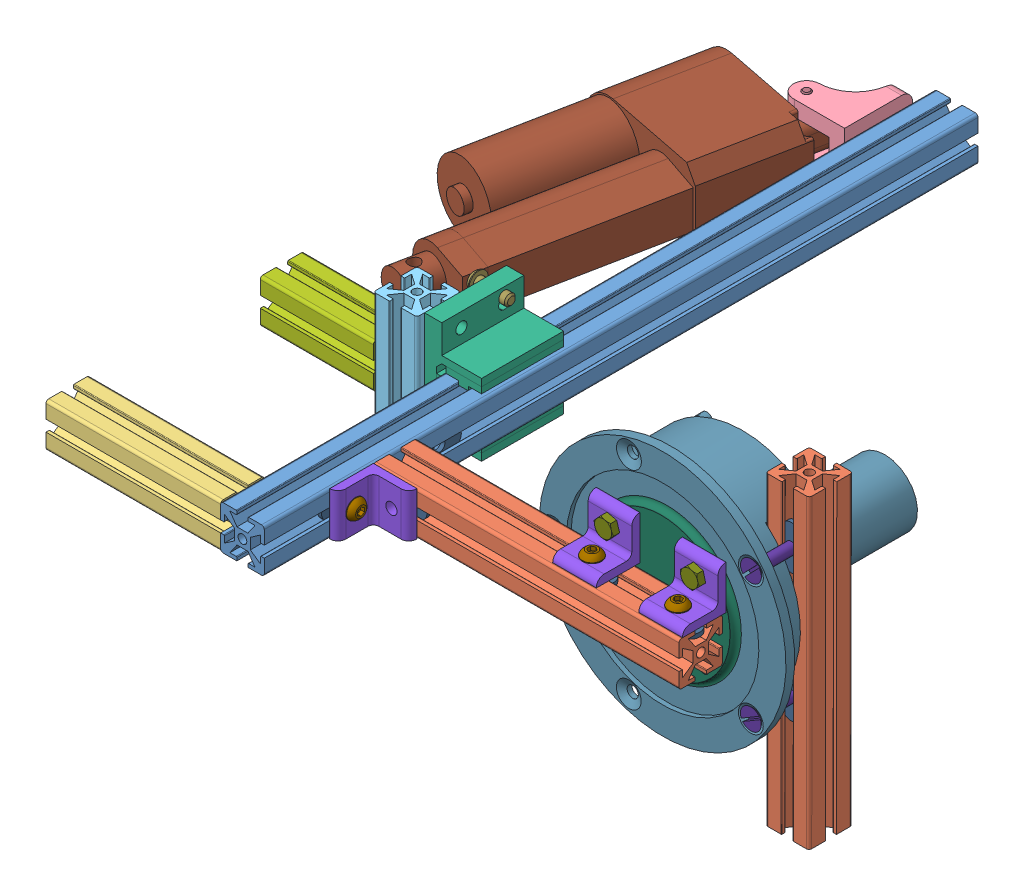
SolidWorks assembly ball manipulator stand, configuration Default. Lengths in mm.
Overall size (319.83 198.44 212.31).
77 component instances, 17 part files, 145 mates.
Components (placement in the parent):
- 80-20 Extrusion- 16.5in-1: 80-20 Extrusion- 16.5in [80-20 Extrusion - 12.0 inch] at (161.9188 214.7859 108.7981) size (25.4 25.4 415.29) (hidden)
- 80-20 Extrusion-7in-1: 80-20 Extrusion-7in [80-20 Extrusion - 12.0 inch] at (352.4188 214.7859 447.8881) x (0 0 1) z (-1 0 0) size (25.4 25.4 177.8)
- 80-20 Extrusion-4in-1: 80-20 Extrusion-4in [80-20 Extrusion - 12.0 inch] at (47.6188 214.7859 511.3881) x (0 0 -1) z (1 0 0) size (25.4 25.4 101.6) (hidden)
- Linear Actuator Mount (10-24)-1: Linear Actuator Mount (10-24) [Default] at (149.2188 233.8359 141.2593) x (0 0 -1) z (0 1 0) size (39.54 37.32 38.1) (hidden)
- 80-20 Extrusion (simplified)-1: 80-20 Extrusion (simplified) [80-20 Extrusion - 12.0 inch] at (126.0142 252.6319 386.5998) x (1 0 0) z (0 -1 0) size (25.4 25.4 101.6) (hidden)
- 80-20 Linear Slide-1: 80-20 Linear Slide [Default] at (171.9374 230.4306 347.2298) x (0 -1 0) z (0 0 1) size (74.8 33.22 47.75) (hidden)
- 80-20 Extrusion-2.59in-1: 80-20 Extrusion-2.59in [80-20 Extrusion - 12.0 inch] at (113.3142 214.7859 386.5998) x (0 0 1) z (-1 0 0) size (25.4 25.4 65.79) (hidden)
- 80-20 90 Degree Bracket Assy-1: 80-20 90 Degree Bracket Assy [Default] at (172.1403 218.357 451.9796) x (0 -1 0) z (0 0 1) size (25.4 35.88 33.34)
  - 80-20 90 Degree Angle Bracket-1: 80-20 90 Degree Angle Bracket [Default] at (-9.1289 2.4785 8.6086) size (25.4 25.4 25.4) (hidden)
  - 0.25-20 Button Head Cap Screw (BHCS)-1: 0.25-20 Button Head Cap Screw (BHCS) [Default] at (3.5711 10.5938 23.8486) x (1 0 0) z (0 -1 0) size (11.1 11.1 16.05) (hidden)
  - 0.25-20 Button Head Cap Screw (BHCS)-2: 0.25-20 Button Head Cap Screw (BHCS) [Default] at (3.5711 17.7185 16.7239) x (1 0 0) z (0 0 -1) size (11.1 11.1 16.05) (hidden)
  - 80-20 0.25-20 T-NUT-2: 80-20 0.25-20 T-NUT [Default] at (-122.3619 -100.634 5.3515) x (0 1 0) z (0 0 -1) size (25.4 11.25 2.41) (hidden)
- 80-20 90 Degree Bracket Assy-2: 80-20 90 Degree Bracket Assy [Default] at (166.0102 218.357 437.6667) x (0 -1 0) z (1 0 0) size (25.4 35.88 33.34)
  - 80-20 90 Degree Angle Bracket-1: 80-20 90 Degree Angle Bracket [Default] at (-9.1289 2.4785 8.6086) size (25.4 25.4 25.4) (hidden)
  - 0.25-20 Button Head Cap Screw (BHCS)-1: 0.25-20 Button Head Cap Screw (BHCS) [Default] at (3.5711 10.5938 23.8486) x (1 0 0) z (0 -1 0) size (11.1 11.1 16.05) (hidden)
  - 0.25-20 Button Head Cap Screw (BHCS)-2: 0.25-20 Button Head Cap Screw (BHCS) [Default] at (3.5711 17.7185 16.7239) x (1 0 0) z (0 0 -1) size (11.1 11.1 16.05) (hidden)
  - 80-20 0.25-20 T-NUT-2: 80-20 0.25-20 T-NUT [Default] at (-122.3619 -100.634 5.3515) x (0 1 0) z (0 0 -1) size (25.4 11.25 2.41) (hidden)
- 80-20 90 Degree Bracket Assy-3: 80-20 90 Degree Bracket Assy [Default] at (115.7927 218.8774 390.1709) x (0 0 -1) z (0 1 0) size (25.4 35.88 33.34) (hidden)
  - 80-20 90 Degree Angle Bracket-1: 80-20 90 Degree Angle Bracket [Default] at (-9.1289 2.4785 8.6086) size (25.4 25.4 25.4) (hidden)
  - 0.25-20 Button Head Cap Screw (BHCS)-1: 0.25-20 Button Head Cap Screw (BHCS) [Default] at (3.5711 10.5938 23.8486) x (1 0 0) z (0 -1 0) size (11.1 11.1 16.05) (hidden)
  - 0.25-20 Button Head Cap Screw (BHCS)-2: 0.25-20 Button Head Cap Screw (BHCS) [Default] at (3.5711 17.7185 16.7239) x (1 0 0) z (0 0 -1) size (11.1 11.1 16.05) (hidden)
  - 80-20 0.25-20 T-NUT-2: 80-20 0.25-20 T-NUT [Default] at (-122.3619 -100.634 5.3515) x (0 1 0) z (0 0 -1) size (25.4 11.25 2.41) (hidden)
- 80-20 90 Degree Bracket Assy-4: 80-20 90 Degree Bracket Assy [Default] at (115.7927 210.6945 383.0286) x (0 0 1) z (0 -1 0) size (25.4 35.88 33.34) (hidden)
  - 80-20 90 Degree Angle Bracket-1: 80-20 90 Degree Angle Bracket [Default] at (-9.1289 2.4785 8.6086) size (25.4 25.4 25.4) (hidden)
  - 0.25-20 Button Head Cap Screw (BHCS)-1: 0.25-20 Button Head Cap Screw (BHCS) [Default] at (3.5711 10.5938 23.8486) x (1 0 0) z (0 -1 0) size (11.1 11.1 16.05) (hidden)
  - 0.25-20 Button Head Cap Screw (BHCS)-2: 0.25-20 Button Head Cap Screw (BHCS) [Default] at (3.5711 17.7185 16.7239) x (1 0 0) z (0 0 -1) size (11.1 11.1 16.05) (hidden)
  - 80-20 0.25-20 T-NUT-2: 80-20 0.25-20 T-NUT [Default] at (-122.3619 -100.634 5.3515) x (0 1 0) z (0 0 -1) size (25.4 11.25 2.41) (hidden)
- 80-20 90 Degree Bracket Assy-6: 80-20 90 Degree Bracket Assy [Default] at (157.8273 211.2148 501.1667) x (0 1 0) z (-1 0 0) size (25.4 35.88 33.34)
  - 80-20 90 Degree Angle Bracket-1: 80-20 90 Degree Angle Bracket [Default] at (-9.1289 2.4785 8.6086) size (25.4 25.4 25.4) (hidden)
  - 0.25-20 Button Head Cap Screw (BHCS)-1: 0.25-20 Button Head Cap Screw (BHCS) [Default] at (3.5711 10.5938 23.8486) x (1 0 0) z (0 -1 0) size (11.1 11.1 16.05) (hidden)
  - 0.25-20 Button Head Cap Screw (BHCS)-2: 0.25-20 Button Head Cap Screw (BHCS) [Default] at (3.5711 17.7185 16.7239) x (1 0 0) z (0 0 -1) size (11.1 11.1 16.05) (hidden)
  - 80-20 0.25-20 T-NUT-2: 80-20 0.25-20 T-NUT [Default] at (-122.3619 -100.634 5.3515) x (0 1 0) z (0 0 -1) size (25.4 11.25 2.41) (hidden)
- Linear Actuator Mount (10-24)-2: Linear Actuator Mount (10-24) [Default] at (93.9594 233.8359 373.8998) x (1 0 0) z (0 1 0) size (39.54 37.32 38.1) (hidden)
- 80-20 90 Degree Angle Bracket-1: 80-20 90 Degree Angle Bracket [Default] at (138.7142 260.3408 373.8998) x (0 -1 0) z (0 0 -1) size (25.4 25.4 25.4) (hidden)
- 80-20 90 Degree Angle Bracket-2: 80-20 90 Degree Angle Bracket [Default] at (138.7142 198.7839 373.8998) x (0 -1 0) z (0 0 -1) size (25.4 25.4 25.4) (hidden)
- 0.25-20 Button Head Cap Screw (BHCS)-1: 0.25-20 Button Head Cap Screw (BHCS) [Default] at (123.4742 247.6408 365.7845) x (0.356485 0.934301 0) z (0 0 1) size (11.1 11.1 16.05) (hidden)
- 0.25-20 Button Head Cap Screw (BHCS)-3: 0.25-20 Button Head Cap Screw (BHCS) [Default] at (123.4742 186.0839 365.7845) x (-1 0 0) z (0 0 1) size (11.1 11.1 16.05) (hidden)
- 80-20 0.25-20 T-NUT-1: 80-20 0.25-20 T-NUT [Default] at (148.798 121.7077 477.0123) x (0 0 -1) z (1 0 0) size (25.4 11.25 2.41) (hidden)
- 80-20 0.25-20 T-NUT-2: 80-20 0.25-20 T-NUT [Default] at (151.211 60.1508 240.3072) x (0 0 1) z (-1 0 0) size (25.4 11.25 2.41) (hidden)
- 80-20 0.25-20 T-NUT-3: 80-20 0.25-20 T-NUT [Default] at (-2.4589 67.7314 378.4504) x (0 1 0) z (0 0 -1) size (25.4 11.25 2.41) (hidden)
- 80-20 0.25-20 T-NUT-4: 80-20 0.25-20 T-NUT [Default] at (249.4072 365.9934 378.4972) x (0 -1 0) z (0 0 -1) size (25.4 11.25 2.41) (hidden)
- 80-20 0.25-20 T-NUT-6: 80-20 0.25-20 T-NUT [Default] at (-36.4836 88.8528 376.0862) size (25.4 11.25 2.41) (hidden)
- 30 IPM Spal Linear Actuator (2in)-1: 30 IPM Spal Linear Actuator (2in) [Default] at (139.9444 214.7351 169.5975) x (0 1 0) z (-0.193962 0 0.981009) size (41.91 81.79 212.74) (hidden)
- 0.25X20-0.75in Cap Screws-1: 0.25X20-0.75in Cap Screws [91255A540] at (130.5989 247.6408 358.6598) x (0 0.042657 0.99909) z (-1 0 0) size (11.1 11.1 22.63) (hidden)
- 0.25X20-0.75in Cap Screws-2: 0.25X20-0.75in Cap Screws [91255A540] at (130.5989 186.0839 358.6598) x (0 -0.97771 -0.209959) z (-1 0 0) size (11.1 11.1 22.63) (hidden)
- 80-20 0.25-20 T-NUT-8: 80-20 0.25-20 T-NUT [Default] at (151.4052 88.8528 249.4519) x (0 0 -1) z (1 0 0) size (25.4 11.25 2.41) (hidden)
- 0.25-20 Button Head Cap Screw (BHCS)-7: 0.25-20 Button Head Cap Screw (BHCS) [Default] at (81.869 214.7859 361.444) x (0.676812 -0.736156 0) z (0 0 1) size (11.1 11.1 16.05) (hidden)
- 0.25-20 Button Head Cap Screw (BHCS)-8: 0.25-20 Button Head Cap Screw (BHCS) [Default] at (136.763 214.7859 131.0993) x (0 -0.924225 -0.381849) z (1 0 0) size (11.1 11.1 16.05) (hidden)
- 0.25-1in Shoulder Screw-1: 0.25-1in Shoulder Screw [90298A542] at (119.5164 194.8596 153.4218) x (-0.70555 0 -0.708661) z (0 -1 0) size (9.53 9.53 39.87) (hidden)
- 0.25-1in Shoulder Screw-2: 0.25-1in Shoulder Screw [90298A542] at (81.7969 194.8596 344.1974) x (0.04349 0 0.999054) z (0 -1 0) size (9.53 9.53 39.87) (hidden)
- 80-20 90 Degree Angle Bracket-3: 80-20 90 Degree Angle Bracket [Default] at (47.6188 227.4371 496.1481) x (0 -1 0) z (-1 0 0) size (25.4 25.4 25.4) (hidden)
- 80-20 90 Degree Angle Bracket-4: 80-20 90 Degree Angle Bracket [Default] at (47.5282 202.0371 401.8398) x (0 1 0) z (-1 0 0) size (25.4 25.4 25.4) (hidden)
- 0.25-20 Button Head Cap Screw (BHCS)-9: 0.25-20 Button Head Cap Screw (BHCS) [Default] at (39.5035 214.7371 511.3881) x (0 -0.069181 -0.997604) z (1 0 0) size (11.1 11.1 16.05) (hidden)
- 0.25-20 Button Head Cap Screw (BHCS)-10: 0.25-20 Button Head Cap Screw (BHCS) [Default] at (39.4129 214.7371 386.5998) x (0 -0.999129 -0.041739) z (1 0 0) size (11.1 11.1 16.05) (hidden)
- 80-20 90 Degree Angle Bracket-5: 80-20 90 Degree Angle Bracket [Default] at (276.909 227.4859 433.1561) size (25.4 25.4 25.4)
- 80-20 90 Degree Angle Bracket-6: 80-20 90 Degree Angle Bracket [Default] at (327.0188 227.4859 433.1561) size (25.4 25.4 25.4)
- 4.5 RPM Globe Gear Motor Assembly-2: 4.5 RPM Globe Gear Motor Assembly [Default] at (307.0217 233.7918 339.4146) x (0.950793 -0.309826 0) z (0 0 -1) size (143.64 143.64 156.93)
  - 4.5 RPM Globe Gear Motor-1: 4.5 RPM Globe Gear Motor [Default] at (12.2608 12.9598 -92.9541) size (143.64 143.64 156.15)
  - 4.5 RPM Globe Gear Motor Face Hub-1: 4.5 RPM Globe Gear Motor Face Hub [Default] at (12.2608 12.9598 -93.7415) x (0.891392 0.453233 0) z (-0.453233 0.891392 0) size (86.36 11.68 86.36)
- M6X1mm-10mm Hex Head-1: M6X1mm-10mm Hex Head [91287A133] at (289.609 242.7259 434.9186) x (0 0 -1) z (-0.953139 -0.302533 0) size (14 11.55 10)
- M6X1mm-10mm Hex Head-2: M6X1mm-10mm Hex Head [91287A133] at (339.7188 242.7259 434.9186) x (0 0 -1) z (-0.967523 -0.252783 0) size (14 11.55 10)
- 0.25-20 Button Head Cap Screw (BHCS)-11: 0.25-20 Button Head Cap Screw (BHCS) [Default] at (289.609 235.6012 448.3961) x (-0.023006 0 0.999735) z (0 -1 0) size (11.1 11.1 16.05)
- 0.25-20 Button Head Cap Screw (BHCS)-12: 0.25-20 Button Head Cap Screw (BHCS) [Default] at (339.7188 235.6012 448.3961) x (0.99867 0 0.051559) z (0 -1 0) size (11.1 11.1 16.05)
- 80-20 0.25-20 T-NUT-9: 80-20 0.25-20 T-NUT [Default] at (171.2564 225.2507 322.4631) x (1 0 0) z (0 -1 0) size (25.4 11.25 2.41)
- 80-20 0.25-20 T-NUT-10: 80-20 0.25-20 T-NUT [Default] at (221.3662 225.2507 322.4631) x (1 0 0) z (0 -1 0) size (25.4 11.25 2.41)
- 80-20 Extrusion-7in-2: 80-20 Extrusion-7in [80-20 Extrusion - 12.0 inch] at (366.0959 287.5742 398.4597) x (1 -0.00085 0) z (-0.00085 -1 0) size (25.4 25.4 177.8)
- 80-20 0.25-20 T-NUT-11: 80-20 0.25-20 T-NUT [Default] at (240.1723 298.7626 406.5115) x (-0.00085 -1 0) z (0 0 1) size (25.4 11.25 2.41)
- 80-20 0.25-20 T-NUT-12: 80-20 0.25-20 T-NUT [Default] at (240.2358 373.4113 406.5115) x (-0.00085 -1 0) z (0 0 1) size (25.4 11.25 2.41)
- 0.25-20 Button Head Cap Screw (BHCS)-13: 0.25-20 Button Head Cap Screw (BHCS) [Default] at (104.1194 214.7859 361.444) size (11.1 11.1 16.05) (hidden)
- 0.25-20 Button Head Cap Screw (BHCS)-14: 0.25-20 Button Head Cap Screw (BHCS) [Default] at (136.763 214.7859 153.3497) x (0 0.094433 -0.995531) z (1 0 0) size (11.1 11.1 16.05) (hidden)
- 80-20 0.25-20 T-NUT-13: 80-20 0.25-20 T-NUT [Default] at (151.4052 88.8528 271.7023) x (0 0 -1) z (1 0 0) size (25.4 11.25 2.41) (hidden)
- 80-20 0.25-20 T-NUT-14: 80-20 0.25-20 T-NUT [Default] at (-14.2332 88.8528 376.0862) size (25.4 11.25 2.41) (hidden)
- 80-20 0.25-20 T-NUT-15: 80-20 0.25-20 T-NUT [Default] at (170.0194 88.8528 594.1807) x (0 0 -1) z (1 0 0) size (25.4 11.25 2.41)
- 80-20 0.25-20 T-NUT-16: 80-20 0.25-20 T-NUT [Default] at (170.0194 88.8528 538.3007) x (0 0 -1) z (1 0 0) size (25.4 11.25 2.41)
- 80-20 0.25-20 T-NUT-17: 80-20 0.25-20 T-NUT [Default] at (71.5062 88.8528 437.3745) size (25.4 11.25 2.41)
- Flat Head-0.25X20-1.125 in Screw-1: Flat Head-0.25X20-1.125 in Screw [90275A543] at (366.0682 254.9517 428.4825) x (0.696419 0.717636 0) z (0 0 1) size (12.02 12.12 28.57)
- Flat Head-0.25X20-1.125 in Screw-2: Flat Head-0.25X20-1.125 in Screw [90275A543] at (366.0047 180.303 428.4825) x (0.86076 0.509011 0) z (0 0 1) size (12.02 12.12 28.57)
Mates (geometry in assembly coordinates):
- Coincident1: coincident anti-aligned: plane of 80-20 Extrusion- 16.5in-1 through (174.6188 202.0859 524.0881) normal (1 0 0); plane of 80-20 Extrusion-7in-1 through (174.6188 227.4859 460.5881) normal (-1 0 0)
- Coincident2: coincident aligned: plane of 80-20 Extrusion- 16.5in-1 through (149.2188 227.4859 524.0881) normal (0 1 0); plane of 80-20 Extrusion-7in-1 through (174.6188 227.4859 435.1881) normal (0 1 0)
- Distance1: distance = 88.9 mm: line of 80-20 Extrusion- 16.5in-1 through (174.6188 218.001 524.0881) axis (0 1 0); plane of 80-20 Extrusion-7in-1 through (174.6188 202.0859 435.1881) normal (0 0 -1)
- Coincident4: coincident anti-aligned: plane of 80-20 Extrusion- 16.5in-1 through (149.2188 202.0859 524.0881) normal (-1 0 0); plane of 80-20 Extrusion-4in-1 through (149.2188 227.4859 498.6881) normal (1 0 0)
- Coincident5: coincident: line of 80-20 Extrusion- 16.5in-1 through (149.2188 211.4732 524.0881) axis (0 -1 0); plane of 80-20 Extrusion-4in-1 through (149.2188 202.0859 524.0881) normal (0 0 1)
- Coincident6: coincident aligned: plane of 80-20 Extrusion- 16.5in-1 through (149.2188 227.4859 524.0881) normal (0 1 0); plane of 80-20 Extrusion-4in-1 through (149.2188 227.4859 524.0881) normal (0 1 0)
- Coincident9: coincident anti-aligned: plane of 80-20 Extrusion- 16.5in-1 through (149.2188 202.0859 524.0881) normal (-1 0 0); plane of Linear Actuator Mount (10-24)-1 through (149.2188 195.7359 161.0205) normal (1 0 0)
- Distance6: distance = 12.7 mm: line of 80-20 Extrusion- 16.5in-1 through (149.2188 211.4732 108.7981) axis (0 -1 0); line of Linear Actuator Mount (10-24)-1 through (149.2188 202.0859 121.4981) axis (0 1 0)
- Distance2: distance = 6.35 mm aligned: plane of Linear Actuator Mount (10-24)-1 through (119.5164 233.8359 153.4218) normal (0 1 0); plane of 80-20 Extrusion- 16.5in-1 through (149.2188 227.4859 524.0881) normal (0 1 0)
- Coincident23: coincident anti-aligned: plane of 80-20 Extrusion- 16.5in-1 through (149.2188 202.0859 524.0881) normal (-1 0 0); plane of 80-20 Linear Slide-1 through (149.2188 218.1914 347.2298) normal (1 0 0)
- Coincident24: coincident anti-aligned: plane of 80-20 Extrusion- 16.5in-1 through (149.2188 202.0859 524.0881) normal (0 -1 0); plane of 80-20 Linear Slide-1 through (158.7294 202.0859 394.9818) normal (0 1 0)
- Coincident25: coincident anti-aligned: plane of 80-20 Extrusion (simplified)-1 through (138.7142 151.0319 373.8998) normal (1 0 0); plane of 80-20 Linear Slide-1 through (138.7142 252.6319 394.9818) normal (-1 0 0)
- Coincident26: coincident: line of 80-20 Extrusion (simplified)-1 through (138.7142 252.6319 389.8149) axis (0 0 1); plane of 80-20 Linear Slide-1 through (148.798 252.6319 394.9818) normal (0 1 0)
- Coincident28: coincident anti-aligned: plane of 80-20 Extrusion (simplified)-1 through (113.3142 151.0319 373.8998) normal (-1 0 0); plane of 80-20 Extrusion-2.59in-1 through (113.3142 227.4859 399.2998) normal (1 0 0)
- Coincident29: coincident: line of 80-20 Extrusion (simplified)-1 through (114.9017 252.6319 399.2998) axis (0 -1 0); plane of 80-20 Extrusion-2.59in-1 through (47.5282 202.0859 399.2998) normal (0 0 1)
- Distance4: distance = 51.054 mm: line of 80-20 Extrusion (simplified)-1 through (113.3142 151.0319 397.7123) axis (0 0 -1); plane of 80-20 Extrusion-2.59in-1 through (47.5282 202.0859 373.8998) normal (0 -1 0)
- Coincident33: coincident anti-aligned: plane of 80-20 Extrusion- 16.5in-1 through (174.6188 202.0859 524.0881) normal (1 0 0); plane of 80-20 90 Degree Bracket Assy-1/80-20 90 Degree Angle Bracket-1 through (174.6188 202.0859 460.5881) normal (-1 0 0)
- Coincident34: coincident aligned: plane of 80-20 Extrusion- 16.5in-1 through (149.2188 227.4859 524.0881) normal (0 1 0); plane of 80-20 90 Degree Bracket Assy-1/80-20 90 Degree Angle Bracket-1 through (174.8093 227.4859 481.4161) normal (0 1 0)
- Coincident35: coincident: plane of 80-20 Extrusion-7in-1 through (174.6188 202.0859 460.5881) normal (0 0 1); line of 80-20 90 Degree Bracket Assy-1/80-20 90 Degree Angle Bracket-1 through (200.0188 227.4859 460.5881) axis (-1 0 0)
- Coincident36: coincident anti-aligned: plane of 80-20 Extrusion-7in-1 through (174.6188 202.0859 435.1881) normal (0 0 -1); plane of 80-20 90 Degree Bracket Assy-2/80-20 90 Degree Angle Bracket-1 through (174.6188 202.0859 435.1881) normal (0 0 1)
- Coincident37: coincident anti-aligned: plane of 80-20 Extrusion- 16.5in-1 through (174.6188 202.0859 524.0881) normal (1 0 0); plane of 80-20 90 Degree Bracket Assy-2/80-20 90 Degree Angle Bracket-1 through (174.6188 202.0859 409.7881) normal (-1 0 0)
- Coincident38: coincident aligned: plane of 80-20 Extrusion-7in-1 through (174.6188 227.4859 435.1881) normal (0 1 0); plane of 80-20 90 Degree Bracket Assy-2/80-20 90 Degree Angle Bracket-1 through (195.4468 227.4859 434.9976) normal (0 1 0)
- Coincident39: coincident anti-aligned: plane of 80-20 Extrusion (simplified)-1 through (113.3142 151.0319 373.8998) normal (-1 0 0); plane of 80-20 90 Degree Bracket Assy-3/80-20 90 Degree Angle Bracket-1 through (113.3142 227.4859 373.8998) normal (1 0 0)
- Coincident40: coincident anti-aligned: plane of 80-20 Extrusion-2.59in-1 through (47.5282 227.4859 373.8998) normal (0 1 0); plane of 80-20 90 Degree Bracket Assy-3/80-20 90 Degree Angle Bracket-1 through (87.9142 227.4859 373.8998) normal (0 -1 0)
- Coincident41: coincident aligned: plane of 80-20 Extrusion (simplified)-1 through (113.3142 151.0319 399.2998) normal (0 0 1); plane of 80-20 90 Degree Bracket Assy-3/80-20 90 Degree Angle Bracket-1 through (113.1237 248.3139 399.2998) normal (0 0 1)
- Coincident42: coincident anti-aligned: plane of 80-20 Extrusion (simplified)-1 through (113.3142 151.0319 373.8998) normal (-1 0 0); plane of 80-20 90 Degree Bracket Assy-4/80-20 90 Degree Angle Bracket-1 through (113.3142 202.0859 399.2998) normal (1 0 0)
- Coincident43: coincident anti-aligned: plane of 80-20 Extrusion-2.59in-1 through (47.5282 202.0859 373.8998) normal (0 -1 0); plane of 80-20 90 Degree Bracket Assy-4/80-20 90 Degree Angle Bracket-1 through (87.9142 202.0859 399.2998) normal (0 1 0)
- Coincident44: coincident aligned: plane of 80-20 Extrusion (simplified)-1 through (113.3142 151.0319 399.2998) normal (0 0 1); plane of 80-20 90 Degree Bracket Assy-4/80-20 90 Degree Angle Bracket-1 through (113.1237 181.2579 399.2998) normal (0 0 1)
- Coincident50: coincident anti-aligned: plane of 80-20 Extrusion- 16.5in-1 through (149.2188 202.0859 524.0881) normal (-1 0 0); plane of 80-20 90 Degree Bracket Assy-6/80-20 90 Degree Angle Bracket-1 through (149.2188 227.4859 473.2881) normal (1 0 0)
- Coincident51: coincident anti-aligned: plane of 80-20 Extrusion-4in-1 through (149.2188 202.0859 498.6881) normal (0 0 -1); plane of 80-20 90 Degree Bracket Assy-6/80-20 90 Degree Angle Bracket-1 through (149.2188 227.4859 498.6881) normal (0 0 1)
- Coincident52: coincident aligned: plane of 80-20 Extrusion-4in-1 through (149.2188 227.4859 524.0881) normal (0 1 0); plane of 80-20 90 Degree Bracket Assy-6/80-20 90 Degree Angle Bracket-1 through (128.3908 227.4859 498.4976) normal (0 1 0)
- Coincident53: coincident anti-aligned: plane of 80-20 Extrusion-2.59in-1 through (47.5282 202.0859 373.8998) normal (0 0 -1); plane of Linear Actuator Mount (10-24)-2 through (74.1982 195.7359 373.8998) normal (0 0 1)
- Distance5: distance = 6.35 mm: line of Linear Actuator Mount (10-24)-2 through (74.1982 233.8359 373.8998) axis (1 0 0); plane of 80-20 Extrusion-2.59in-1 through (47.5282 227.4859 373.8998) normal (0 1 0)
- Concentric1: concentric anti-aligned: circle of 80-20 90 Degree Angle Bracket-1; circle of 0.25-20 Button Head Cap Screw (BHCS)-1
- Coincident54: coincident anti-aligned: plane of 80-20 90 Degree Angle Bracket-1 through (130.7767 234.9408 369.1373) normal (0 0 -1); plane of 0.25-20 Button Head Cap Screw (BHCS)-1 through (125.4526 252.8261 369.1373) normal (0 0 1)
- Concentric2: concentric aligned: cylinder of 0.25-20 Button Head Cap Screw (BHCS)-1 through (123.4742 247.6408 381.8373) axis (0 0 -1) radius 3.175; cylinder of 80-20 0.25-20 T-NUT-4 through (123.4742 247.6408 378.4982) axis (0 0 -1) radius 3.175
- Distance7: distance = 2.1844 mm anti-aligned: plane of 80-20 90 Degree Angle Bracket-1 through (113.3142 234.9408 373.8998) normal (0 0 1); plane of 80-20 0.25-20 T-NUT-4 through (123.4742 254.7147 376.0842) normal (0 0 -1)
- Parallel3: parallel anti-aligned: line of 80-20 0.25-20 T-NUT-4 through (129.1003 254.7147 376.0842) axis (0 -1 0); line of 80-20 90 Degree Angle Bracket-1 through (138.7142 234.9408 373.8998) axis (0 1 0)
- Parallel6: parallel aligned: line of 80-20 Linear Slide-1 through (138.7142 252.6319 394.9818) axis (0 0 -1); line of 80-20 90 Degree Angle Bracket-1 through (138.7142 260.3408 373.8998) axis (0 0 -1)
- Coincident65: coincident anti-aligned: plane of 80-20 Linear Slide-1 through (138.7142 252.6319 394.9818) normal (-1 0 0); plane of 80-20 90 Degree Angle Bracket-1 through (138.7142 234.9408 373.8998) normal (1 0 0)
- Coincident66: coincident anti-aligned: plane of 80-20 Extrusion (simplified)-1 through (113.3142 151.0319 373.8998) normal (0 0 -1); plane of 80-20 90 Degree Angle Bracket-1 through (113.3142 234.9408 373.8998) normal (0 0 1)
- Coincident70: coincident anti-aligned: plane of 80-20 Linear Slide-1 through (148.798 236.1219 394.9818) normal (1 0 0); plane of 80-20 0.25-20 T-NUT-1 through (148.798 247.6408 365.7337) normal (-1 0 0)
- Concentric16: concentric anti-aligned: cylinder of 80-20 90 Degree Angle Bracket-2 through (123.4742 186.0839 373.8998) axis (0 0 1) radius 3.2639; cylinder of 0.25-20 Button Head Cap Screw (BHCS)-3 through (123.4742 186.0839 381.8373) axis (0 0 -1) radius 3.175
- Coincident75: coincident anti-aligned: plane of 80-20 90 Degree Angle Bracket-2 through (130.7767 173.3839 369.1373) normal (0 0 -1); plane of 0.25-20 Button Head Cap Screw (BHCS)-3 through (117.9243 186.0839 369.1373) normal (0 0 1)
- Coincident77: coincident anti-aligned: plane of 80-20 Extrusion (simplified)-1 through (126.0142 269.3711 376.0374) normal (0 0 1); plane of 80-20 0.25-20 T-NUT-3 through (123.4742 179.01 376.0374) normal (0 0 -1)
- Coincident78: coincident anti-aligned: plane of 80-20 Extrusion (simplified)-1 through (113.3142 151.0319 373.8998) normal (0 0 -1); plane of 80-20 90 Degree Angle Bracket-2 through (113.3142 173.3839 373.8998) normal (0 0 1)
- Coincident79: coincident anti-aligned: plane of 80-20 Linear Slide-1 through (138.7142 252.6319 394.9818) normal (-1 0 0); plane of 80-20 90 Degree Angle Bracket-2 through (138.7142 173.3839 373.8998) normal (1 0 0)
- Concentric18: concentric aligned: cylinder of 0.25-20 Button Head Cap Screw (BHCS)-3 through (123.4742 186.0839 381.8373) axis (0 0 -1) radius 3.175; cylinder of 80-20 0.25-20 T-NUT-3 through (123.4742 186.0839 378.4514) axis (0 0 -1) radius 3.175
- Parallel9: parallel aligned: line of 80-20 90 Degree Angle Bracket-2 through (113.3142 173.3839 373.8998) axis (0 1 0); line of 80-20 0.25-20 T-NUT-3 through (117.8481 179.01 378.4504) axis (0 1 0)
- Concentric19: concentric aligned: cylinder of 80-20 Linear Slide-1 through (21.798 186.0839 358.6598) axis (1 0 0) radius 3.2639; cylinder of 80-20 90 Degree Angle Bracket-2 through (138.7142 186.0839 358.6598) axis (1 0 0) radius 3.2639
- Coincident82: coincident anti-aligned: plane of 80-20 Linear Slide-1 through (148.798 194.3389 394.9818) normal (1 0 0); plane of 80-20 0.25-20 T-NUT-2 through (148.798 186.0839 351.5859) normal (-1 0 0)
- Parallel10: parallel anti-aligned: line of 80-20 Linear Slide-1 through (148.798 177.8289 394.9818) axis (0 0 -1); line of 80-20 0.25-20 T-NUT-2 through (151.211 180.4578 351.5859) axis (0 0 1)
- Concentric24: concentric anti-aligned: circle of Linear Actuator Mount (10-24)-1; cylinder of 30 IPM Spal Linear Actuator (2in)-1 through (119.5164 193.7801 153.4218) axis (0 1 0) radius 3.3782
- Concentric26: concentric aligned: cylinder of Linear Actuator Mount (10-24)-2 through (81.7969 233.8359 344.1974) axis (0 1 0) radius 1.8986; cylinder of 30 IPM Spal Linear Actuator (2in)-1 through (81.7969 193.7801 344.1974) axis (0 1 0) radius 3.3782
- Tangent2: tangent anti-aligned: plane of Linear Actuator Mount (10-24)-2 through (113.7206 204.7529 364.7968) normal (0 1 0); cylinder of 30 IPM Spal Linear Actuator (2in)-1 through (79.9494 214.7351 353.5415) axis (0.193962 0 -0.981009) radius 9.9822
- Concentric32: concentric anti-aligned: circle of 80-20 90 Degree Angle Bracket-1; circle of 0.25X20-0.75in Cap Screws-1
- Coincident108: coincident aligned: circle of 80-20 0.25-20 T-NUT-1; cylinder of 0.25X20-0.75in Cap Screws-1 through (153.0017 247.6408 358.6598) axis (1 0 0) radius 3.175
- Coincident109: coincident anti-aligned: plane of 80-20 90 Degree Angle Bracket-1 through (133.9517 234.9408 353.0718) normal (-1 0 0); plane of 0.25X20-0.75in Cap Screws-1 through (133.9517 242.096 358.8965) normal (1 0 0)
- Coincident111: coincident: cylinder of 80-20 Linear Slide-1 through (21.798 244.3769 358.6598) axis (1 0 0) radius 3.2639; line of 0.25X20-0.75in Cap Screws-1 through (153.0017 247.6408 358.6598) axis (-1 0 0)
- Parallel19: parallel anti-aligned: line of 80-20 Linear Slide-1 through (148.798 252.6319 394.9818) axis (0 0 -1); line of 80-20 0.25-20 T-NUT-1 through (151.211 253.2669 351.5859) axis (0 0 1)
- Concentric33: concentric aligned: cylinder of 80-20 Linear Slide-1 through (21.798 186.0839 358.6598) axis (1 0 0) radius 3.2639; cylinder of 0.25X20-0.75in Cap Screws-2 through (153.0017 186.0839 358.6598) axis (1 0 0) radius 3.175
- Coincident113: coincident anti-aligned: plane of 80-20 90 Degree Angle Bracket-2 through (133.9517 173.3839 353.0718) normal (-1 0 0); plane of 0.25X20-0.75in Cap Screws-2 through (133.9517 187.2492 353.2336) normal (1 0 0)
- Concentric34: concentric anti-aligned: cylinder of 80-20 0.25-20 T-NUT-2 through (151.212 186.0839 358.6598) axis (-1 0 0) radius 3.175; cylinder of 0.25X20-0.75in Cap Screws-2 through (153.0017 186.0839 358.6598) axis (1 0 0) radius 3.175
- Coincident114: coincident anti-aligned: plane of 80-20 Linear Slide-1 through (148.798 194.3389 394.9818) normal (1 0 0); plane of 80-20 0.25-20 T-NUT-2 through (148.798 186.0839 351.5859) normal (-1 0 0)
- Parallel20: parallel anti-aligned: line of 80-20 Linear Slide-1 through (148.798 177.8289 394.9818) axis (0 0 -1); line of 80-20 0.25-20 T-NUT-2 through (151.211 180.4578 351.5859) axis (0 0 1)
- Parallel21: parallel anti-aligned: line of Linear Actuator Mount (10-24)-2 through (74.1982 233.8359 373.8998) axis (1 0 0); line of 80-20 0.25-20 T-NUT-6 through (88.9429 220.412 378.4992) axis (-1 0 0)
- Coincident121: coincident anti-aligned: plane of 80-20 Extrusion-2.59in-1 through (130.0533 214.7371 376.0862) normal (0 0 1); plane of 80-20 0.25-20 T-NUT-6 through (74.7951 214.7859 376.0862) normal (0 0 -1)
- Parallel22: parallel anti-aligned: line of Linear Actuator Mount (10-24)-2 through (74.1982 233.8359 373.8998) axis (1 0 0); line of 80-20 0.25-20 T-NUT-6 through (88.9429 220.412 378.4992) axis (-1 0 0)
- Concentric40: concentric anti-aligned: cylinder of Linear Actuator Mount (10-24)-2 through (81.869 214.7859 336.5774) axis (0 0 1) radius 3.4925; cylinder of 0.25-20 Button Head Cap Screw (BHCS)-7 through (81.869 214.7859 377.4968) axis (0 0 -1) radius 3.175
- Coincident123: coincident anti-aligned: plane of Linear Actuator Mount (10-24)-2 through (113.7206 224.8189 364.7968) normal (0 0 -1); plane of 0.25-20 Button Head Cap Screw (BHCS)-7 through (85.6252 210.7003 364.7968) normal (0 0 1)
- Concentric41: concentric aligned: circle of Linear Actuator Mount (10-24)-2; cylinder of 80-20 0.25-20 T-NUT-6 through (81.869 214.7859 376.0852) axis (0 0 1) radius 3.175
- Concentric42: concentric aligned: cylinder of Linear Actuator Mount (10-24)-1 through (111.8964 214.7859 131.0993) axis (1 0 0) radius 3.4925; circle of 0.25-20 Button Head Cap Screw (BHCS)-8
- Coincident124: coincident anti-aligned: plane of Linear Actuator Mount (10-24)-1 through (140.1158 224.8189 121.4981) normal (-1 0 0); plane of 0.25-20 Button Head Cap Screw (BHCS)-8 through (140.1158 209.6566 128.9801) normal (1 0 0)
- Concentric43: concentric anti-aligned: circle of 80-20 0.25-20 T-NUT-8; cylinder of 0.25-20 Button Head Cap Screw (BHCS)-8 through (152.8158 214.7859 131.0993) axis (-1 0 0) radius 3.175
- Coincident126: coincident anti-aligned: plane of 80-20 Extrusion- 16.5in-1 through (151.4052 214.7371 92.059) normal (1 0 0); plane of 80-20 0.25-20 T-NUT-8 through (151.4052 214.7859 138.1732) normal (-1 0 0)
- Concentric45: concentric anti-aligned: cylinder of Linear Actuator Mount (10-24)-1 through (119.5164 195.7359 153.4218) axis (0 -1 0) radius 3.1877; circle of 0.25-1in Shoulder Screw-1
- Coincident128: coincident anti-aligned: plane of Linear Actuator Mount (10-24)-1 through (119.5164 199.6221 150.2341) normal (0 -1 0); plane of 0.25-1in Shoulder Screw-1 through (116.1414 199.6221 156.7819) normal (0 1 0)
- Concentric46: concentric anti-aligned: cylinder of Linear Actuator Mount (10-24)-2 through (81.7969 195.7359 344.1974) axis (0 -1 0) radius 3.1877; cylinder of 0.25-1in Shoulder Screw-2 through (81.7969 234.5471 344.1974) axis (0 1 0) radius 3.175
- Coincident129: coincident anti-aligned: plane of Linear Actuator Mount (10-24)-2 through (84.9846 199.6221 344.1974) normal (0 -1 0); plane of 0.25-1in Shoulder Screw-2 through (86.5549 199.6221 343.9903) normal (0 1 0)
- Distance12: distance = 26.67 mm: plane of Linear Actuator Mount (10-24)-2 through (74.1982 195.7359 373.8998) normal (-1 0 0); line of 80-20 Extrusion-2.59in-1 through (47.5282 211.4732 373.8998) axis (0 -1 0)
- Coincident134: coincident anti-aligned: plane of 80-20 Extrusion-4in-1 through (47.6188 227.4859 498.6881) normal (-1 0 0); plane of 80-20 90 Degree Angle Bracket-3 through (47.6188 202.0371 521.5481) normal (1 0 0)
- Coincident138: coincident anti-aligned: plane of 80-20 Extrusion-2.59in-1 through (47.5282 227.4859 399.2998) normal (-1 0 0); plane of 80-20 90 Degree Angle Bracket-4 through (47.5282 227.4371 376.4398) normal (1 0 0)
- Concentric51: concentric aligned: circle of 80-20 Extrusion-2.59in-1; circle of 80-20 90 Degree Angle Bracket-4
- Parallel28: parallel aligned: plane of 80-20 Extrusion-2.59in-1 through (47.5282 202.0859 399.2998) normal (0 0 1); plane of 80-20 90 Degree Angle Bracket-4 through (47.5282 227.4371 401.8398) normal (0 0 1)
- Concentric52: concentric anti-aligned: circle of 80-20 Extrusion-4in-1; circle of 80-20 90 Degree Angle Bracket-3
- Parallel29: parallel: plane of 80-20 Extrusion-4in-1 through (149.2188 202.0859 524.0881) normal (0 -1 0); line of 80-20 90 Degree Angle Bracket-3 through (47.6188 202.0371 521.5481) axis (0 0 -1)
- Concentric53: concentric anti-aligned: cylinder of 80-20 90 Degree Angle Bracket-3 through (47.6188 214.7371 511.3881) axis (1 0 0) radius 3.2639; cylinder of 0.25-20 Button Head Cap Screw (BHCS)-9 through (55.5563 214.7371 511.3881) axis (-1 0 0) radius 3.175
- Coincident143: coincident anti-aligned: plane of 80-20 90 Degree Angle Bracket-3 through (42.8563 202.0371 504.0856) normal (-1 0 0); circle of 0.25-20 Button Head Cap Screw (BHCS)-9
- Concentric54: concentric aligned: circle of 80-20 90 Degree Angle Bracket-4; cylinder of 0.25-20 Button Head Cap Screw (BHCS)-10 through (55.4657 214.7371 386.5998) axis (-1 0 0) radius 3.175
- Coincident144: coincident anti-aligned: plane of 80-20 90 Degree Angle Bracket-4 through (42.7657 227.4371 393.9023) normal (-1 0 0); plane of 0.25-20 Button Head Cap Screw (BHCS)-10 through (42.7657 209.1921 386.3681) normal (1 0 0)
- Coincident154: coincident anti-aligned: plane of 80-20 Extrusion-7in-1 through (174.6188 227.4859 435.1881) normal (0 1 0); plane of 80-20 90 Degree Angle Bracket-5 through (302.309 227.4859 433.1561) normal (0 -1 0)
- Coincident155: coincident anti-aligned: plane of 80-20 Extrusion-7in-1 through (174.6188 227.4859 435.1881) normal (0 1 0); plane of 80-20 90 Degree Angle Bracket-6 through (352.4188 227.4859 433.1561) normal (0 -1 0)
- Distance14: distance = 2.032 mm aligned: plane of 80-20 90 Degree Angle Bracket-5 through (302.309 252.8859 433.1561) normal (0 0 -1); plane of 80-20 Extrusion-7in-1 through (174.6188 202.0859 435.1881) normal (0 0 -1)
- Coincident161: coincident anti-aligned: plane of 80-20 90 Degree Angle Bracket-6 through (352.4188 252.8859 433.1561) normal (0 0 -1); plane of 4.5 RPM Globe Gear Motor Assembly-2/4.5 RPM Globe Gear Motor Face Hub-1 through (314.6639 217.671 433.1561) normal (0 0 1)
- Coincident162: coincident anti-aligned: plane of 80-20 90 Degree Angle Bracket-5 through (302.309 235.4234 437.9186) normal (0 0 1); plane of M6X1mm-10mm Hex Head-1 through (293.5013 246.9901 437.9186) normal (0 0 -1)
- Coincident163: coincident anti-aligned: plane of 80-20 90 Degree Angle Bracket-6 through (352.4188 235.4234 437.9186) normal (0 0 1); plane of M6X1mm-10mm Hex Head-2 through (343.8267 246.7828 437.9186) normal (0 0 -1)
- Concentric63: concentric anti-aligned: cylinder of 0.25-20 Button Head Cap Screw (BHCS)-11 through (289.609 219.5484 448.3961) axis (0 1 0) radius 3.175; cylinder of 80-20 0.25-20 T-NUT-9 through (289.609 225.2517 448.3961) axis (0 -1 0) radius 3.175
- Concentric64: concentric anti-aligned: cylinder of 80-20 90 Degree Angle Bracket-5 through (289.609 227.4859 448.3961) axis (0 -1 0) radius 3.2639; cylinder of 0.25-20 Button Head Cap Screw (BHCS)-11 through (289.609 219.5484 448.3961) axis (0 1 0) radius 3.175
- Coincident165: coincident anti-aligned: plane of 80-20 90 Degree Angle Bracket-5 through (302.309 232.2484 453.9841) normal (0 1 0); plane of 0.25-20 Button Head Cap Screw (BHCS)-11 through (289.4813 232.2484 453.9446) normal (0 -1 0)
- Concentric65: concentric anti-aligned: cylinder of 0.25-20 Button Head Cap Screw (BHCS)-12 through (339.7188 219.5484 448.3961) axis (0 1 0) radius 3.175; cylinder of 80-20 0.25-20 T-NUT-10 through (339.7188 225.2517 448.3961) axis (0 -1 0) radius 3.175
- Concentric66: concentric anti-aligned: cylinder of 80-20 90 Degree Angle Bracket-6 through (339.7188 227.4859 448.3961) axis (0 -1 0) radius 3.2639; cylinder of 0.25-20 Button Head Cap Screw (BHCS)-12 through (339.7188 219.5484 448.3961) axis (0 1 0) radius 3.175
- Parallel34: parallel aligned: line of 80-20 90 Degree Angle Bracket-6 through (352.4188 232.2484 453.9841) axis (-1 0 0); line of 80-20 0.25-20 T-NUT-10 through (346.7927 225.2507 454.0222) axis (-1 0 0)
- Coincident168: coincident anti-aligned: plane of 80-20 Extrusion-7in-1 through (369.1579 225.2507 447.8881) normal (0 -1 0); plane of 80-20 0.25-20 T-NUT-10 through (332.6449 225.2507 448.3961) normal (0 1 0)
- Coincident169: coincident anti-aligned: plane of 80-20 90 Degree Angle Bracket-6 through (352.4188 232.2484 453.9841) normal (0 1 0); plane of 0.25-20 Button Head Cap Screw (BHCS)-12 through (345.2613 232.2484 448.6823) normal (0 -1 0)
- Parallel36: parallel aligned: line of 80-20 90 Degree Angle Bracket-5 through (302.309 232.2484 453.9841) axis (-1 0 0); line of 80-20 0.25-20 T-NUT-9 through (296.6829 225.2507 454.0222) axis (-1 0 0)
- Coincident172: coincident anti-aligned: plane of 80-20 Extrusion-7in-1 through (369.1579 225.2507 447.8881) normal (0 -1 0); plane of 80-20 0.25-20 T-NUT-9 through (282.5351 225.2507 448.3961) normal (0 1 0)
- Coincident173: coincident: line of 80-20 Extrusion-7in-1 through (352.4188 227.4859 444.2274) axis (0 0 -1); plane of 80-20 90 Degree Angle Bracket-6 through (352.4188 227.6764 453.9841) normal (1 0 0)
- Concentric67: concentric anti-aligned: cylinder of M6X1mm-10mm Hex Head-1 through (289.609 242.7259 437.9186) axis (0 0 -1) radius 3; cylinder of 4.5 RPM Globe Gear Motor Assembly-2/4.5 RPM Globe Gear Motor Face Hub-1 through (289.609 242.7259 433.1561) axis (0 0 1) radius 2.5
- Concentric68: concentric aligned: cylinder of 80-20 90 Degree Angle Bracket-5 through (289.609 242.7259 433.1561) axis (0 0 -1) radius 3.2639; cylinder of M6X1mm-10mm Hex Head-1 through (289.609 242.7259 437.9186) axis (0 0 -1) radius 3
- Concentric69: concentric anti-aligned: circle of 80-20 90 Degree Angle Bracket-6; cylinder of M6X1mm-10mm Hex Head-2 through (339.7188 242.7259 437.9186) axis (0 0 -1) radius 3
- Concentric70: concentric aligned: circle of M6X1mm-10mm Hex Head-2; circle of 4.5 RPM Globe Gear Motor Assembly-2/4.5 RPM Globe Gear Motor Face Hub-1
- Coincident175: coincident anti-aligned: plane of 80-20 90 Degree Angle Bracket-5 through (302.309 252.8859 433.1561) normal (0 0 -1); plane of 4.5 RPM Globe Gear Motor Assembly-2/4.5 RPM Globe Gear Motor Face Hub-1 through (314.6639 217.671 433.1561) normal (0 0 1)
- Coincident176: coincident anti-aligned: plane of 4.5 RPM Globe Gear Motor Assembly-2/4.5 RPM Globe Gear Motor-1 through (353.2986 173.0912 411.1597) normal (0 0 -1); plane of 80-20 Extrusion-7in-2 through (353.2447 109.7851 411.1597) normal (0 0 1)
- Coincident177: coincident anti-aligned: plane of 4.5 RPM Globe Gear Motor Assembly-2/4.5 RPM Globe Gear Motor-1 through (353.2986 173.0912 411.1597) normal (1 -0.00085 0); plane of 80-20 Extrusion-7in-2 through (353.2447 109.7851 385.7597) normal (-1 0.00085 0)
- Distance15: distance = 25.4 mm: line of 4.5 RPM Globe Gear Motor Assembly-2/4.5 RPM Globe Gear Motor-1 through (353.3743 262.185 411.1597) axis (0 0 -1); line of 80-20 Extrusion-7in-2 through (353.3959 287.585 409.5722) axis (0 0 -1)
- Parallel37: parallel aligned: line of 80-20 Extrusion-7in-2 through (377.0572 109.7648 411.1597) axis (0.00085 1 0); line of 80-20 0.25-20 T-NUT-12 through (371.6883 247.873 408.9245) axis (0.00085 1 0)
- Parallel38: parallel aligned: line of 80-20 Extrusion-7in-2 through (377.0572 109.7648 411.1597) axis (0.00085 1 0); line of 80-20 0.25-20 T-NUT-11 through (371.6248 173.2243 408.9245) axis (0.00085 1 0)
- Coincident183: coincident anti-aligned: plane of 80-20 Extrusion-7in-2 through (366.1101 304.3133 408.9245) normal (0 0 -1); plane of 80-20 0.25-20 T-NUT-11 through (366.0107 187.3769 408.9245) normal (0 0 1)
- Coincident184: coincident anti-aligned: plane of 80-20 Extrusion-7in-2 through (366.1101 304.3133 408.9245) normal (0 0 -1); plane of 80-20 0.25-20 T-NUT-12 through (366.0742 262.0256 408.9245) normal (0 0 1)
- Concentric73: concentric anti-aligned: cylinder of Linear Actuator Mount (10-24)-2 through (104.1194 214.7859 336.5774) axis (0 0 1) radius 3.4925; cylinder of 0.25-20 Button Head Cap Screw (BHCS)-13 through (104.1194 214.7859 377.4968) axis (0 0 -1) radius 3.175
- Concentric74: concentric anti-aligned: cylinder of 0.25-20 Button Head Cap Screw (BHCS)-13 through (104.1194 214.7859 377.4968) axis (0 0 -1) radius 3.175; cylinder of 80-20 0.25-20 T-NUT-14 through (104.1194 214.7859 376.0852) axis (0 0 1) radius 3.175
- Parallel39: parallel aligned: plane of 80-20 Extrusion-2.59in-1 through (47.5282 227.4859 373.8998) normal (0 1 0); plane of 80-20 0.25-20 T-NUT-14 through (97.0455 220.412 378.4992) normal (0 1 0)
- Coincident187: coincident anti-aligned: plane of 80-20 Extrusion-2.59in-1 through (130.0533 214.7371 376.0862) normal (0 0 1); plane of 80-20 0.25-20 T-NUT-14 through (97.0455 214.7859 376.0862) normal (0 0 -1)
- Coincident188: coincident anti-aligned: plane of Linear Actuator Mount (10-24)-2 through (113.7206 224.8189 364.7968) normal (0 0 -1); plane of 0.25-20 Button Head Cap Screw (BHCS)-13 through (109.6693 214.7859 364.7968) normal (0 0 1)
- Concentric75: concentric anti-aligned: cylinder of Linear Actuator Mount (10-24)-1 through (111.8964 214.7859 153.3497) axis (1 0 0) radius 3.4925; cylinder of 0.25-20 Button Head Cap Screw (BHCS)-14 through (152.8158 214.7859 153.3497) axis (-1 0 0) radius 3.175
- Concentric76: concentric anti-aligned: cylinder of 0.25-20 Button Head Cap Screw (BHCS)-14 through (152.8158 214.7859 153.3497) axis (-1 0 0) radius 3.175; cylinder of 80-20 0.25-20 T-NUT-13 through (151.4042 214.7859 153.3497) axis (1 0 0) radius 3.175
- Parallel40: parallel aligned: plane of 80-20 Extrusion- 16.5in-1 through (149.2188 227.4859 524.0881) normal (0 1 0); plane of 80-20 0.25-20 T-NUT-13 through (153.8182 220.412 160.4236) normal (0 1 0)
- Coincident190: coincident anti-aligned: plane of 80-20 Extrusion- 16.5in-1 through (151.4052 214.7371 92.059) normal (1 0 0); plane of 80-20 0.25-20 T-NUT-13 through (151.4052 214.7859 160.4236) normal (-1 0 0)
- Coincident191: coincident anti-aligned: plane of Linear Actuator Mount (10-24)-1 through (140.1158 224.8189 121.4981) normal (-1 0 0); plane of 0.25-20 Button Head Cap Screw (BHCS)-14 through (140.1158 215.31 147.8246) normal (1 0 0)
- Parallel41: parallel anti-aligned: plane of 80-20 90 Degree Bracket Assy-1/80-20 90 Degree Angle Bracket-1 through (174.6188 202.0859 460.5881) normal (-1 0 0); plane of 80-20 0.25-20 T-NUT-15 through (172.4324 214.7859 482.902) normal (1 0 0)
- Concentric77: concentric aligned: cylinder of 80-20 90 Degree Bracket Assy-1/0.25-20 Button Head Cap Screw (BHCS)-1 through (166.6813 214.7859 475.8281) axis (1 0 0) radius 3.175; cylinder of 80-20 0.25-20 T-NUT-15 through (170.0184 214.7859 475.8281) axis (1 0 0) radius 3.175
- Coincident194: coincident anti-aligned: plane of 80-20 Extrusion- 16.5in-1 through (172.4324 214.7371 92.059) normal (-1 0 0); plane of 80-20 0.25-20 T-NUT-15 through (172.4324 214.7859 482.902) normal (1 0 0)
- Parallel42: parallel aligned: plane of 80-20 Extrusion- 16.5in-1 through (149.2188 227.4859 524.0881) normal (0 1 0); plane of 80-20 0.25-20 T-NUT-15 through (172.4324 220.412 482.902) normal (0 1 0)
- Concentric79: concentric aligned: cylinder of 80-20 90 Degree Bracket Assy-2/0.25-20 Button Head Cap Screw (BHCS)-2 through (166.6813 214.7859 419.9481) axis (1 0 0) radius 3.175; cylinder of 80-20 0.25-20 T-NUT-16 through (170.0184 214.7859 419.9481) axis (1 0 0) radius 3.175
- Parallel44: parallel aligned: plane of 80-20 90 Degree Bracket Assy-2/80-20 90 Degree Angle Bracket-1 through (195.4468 227.4859 434.9976) normal (0 1 0); plane of 80-20 0.25-20 T-NUT-16 through (172.4324 220.412 427.022) normal (0 1 0)
- Coincident200: coincident anti-aligned: plane of 80-20 Extrusion- 16.5in-1 through (172.4324 214.7371 92.059) normal (-1 0 0); plane of 80-20 0.25-20 T-NUT-16 through (172.4324 214.7859 427.022) normal (1 0 0)
- Concentric80: concentric anti-aligned: cylinder of 80-20 90 Degree Bracket Assy-2/0.25-20 Button Head Cap Screw (BHCS)-1 through (189.8588 214.7859 443.1256) axis (0 0 -1) radius 3.175; cylinder of 80-20 0.25-20 T-NUT-17 through (189.8588 214.7859 437.3735) axis (0 0 1) radius 3.175
- Parallel45: parallel aligned: plane of 80-20 90 Degree Bracket Assy-2/80-20 90 Degree Angle Bracket-1 through (195.4468 227.4859 434.9976) normal (0 1 0); plane of 80-20 0.25-20 T-NUT-17 through (182.7849 220.412 439.7875) normal (0 1 0)
- Coincident202: coincident anti-aligned: plane of 80-20 Extrusion-7in-1 through (369.1579 214.7371 437.3745) normal (0 0 1); plane of 80-20 0.25-20 T-NUT-17 through (182.7849 214.7859 437.3745) normal (0 0 -1)
- Concentric81: concentric anti-aligned: circle of 4.5 RPM Globe Gear Motor Assembly-2/4.5 RPM Globe Gear Motor-1; cylinder of Flat Head-0.25X20-1.125 in Screw-1 through (366.0682 254.9517 432.3687) axis (0 0 1) radius 3.175
- Coincident203: coincident aligned: circle of 80-20 0.25-20 T-NUT-12; cylinder of Flat Head-0.25X20-1.125 in Screw-1 through (366.0682 254.9517 432.3687) axis (0 0 1) radius 3.175
- Coincident204: coincident aligned: plane of 4.5 RPM Globe Gear Motor Assembly-2/4.5 RPM Globe Gear Motor-1 through (312.6571 211.5127 432.3687) normal (0 0 1); plane of Flat Head-0.25X20-1.125 in Screw-1 through (363.7897 257.1628 432.3687) normal (0 0 1)
- Concentric82: concentric aligned: circle of 4.5 RPM Globe Gear Motor Assembly-2/4.5 RPM Globe Gear Motor-1; cylinder of Flat Head-0.25X20-1.125 in Screw-2 through (366.0047 180.303 432.3687) axis (0 0 1) radius 3.175
- Concentric83: concentric aligned: cylinder of 80-20 0.25-20 T-NUT-11 through (366.0047 180.303 406.5105) axis (0 0 1) radius 3.175; cylinder of Flat Head-0.25X20-1.125 in Screw-2 through (366.0047 180.303 432.3687) axis (0 0 1) radius 3.175
- Coincident205: coincident aligned: plane of 4.5 RPM Globe Gear Motor Assembly-2/4.5 RPM Globe Gear Motor-1 through (312.6571 211.5127 432.3687) normal (0 0 1); plane of Flat Head-0.25X20-1.125 in Screw-2 through (364.3886 183.0359 432.3687) normal (0 0 1)
